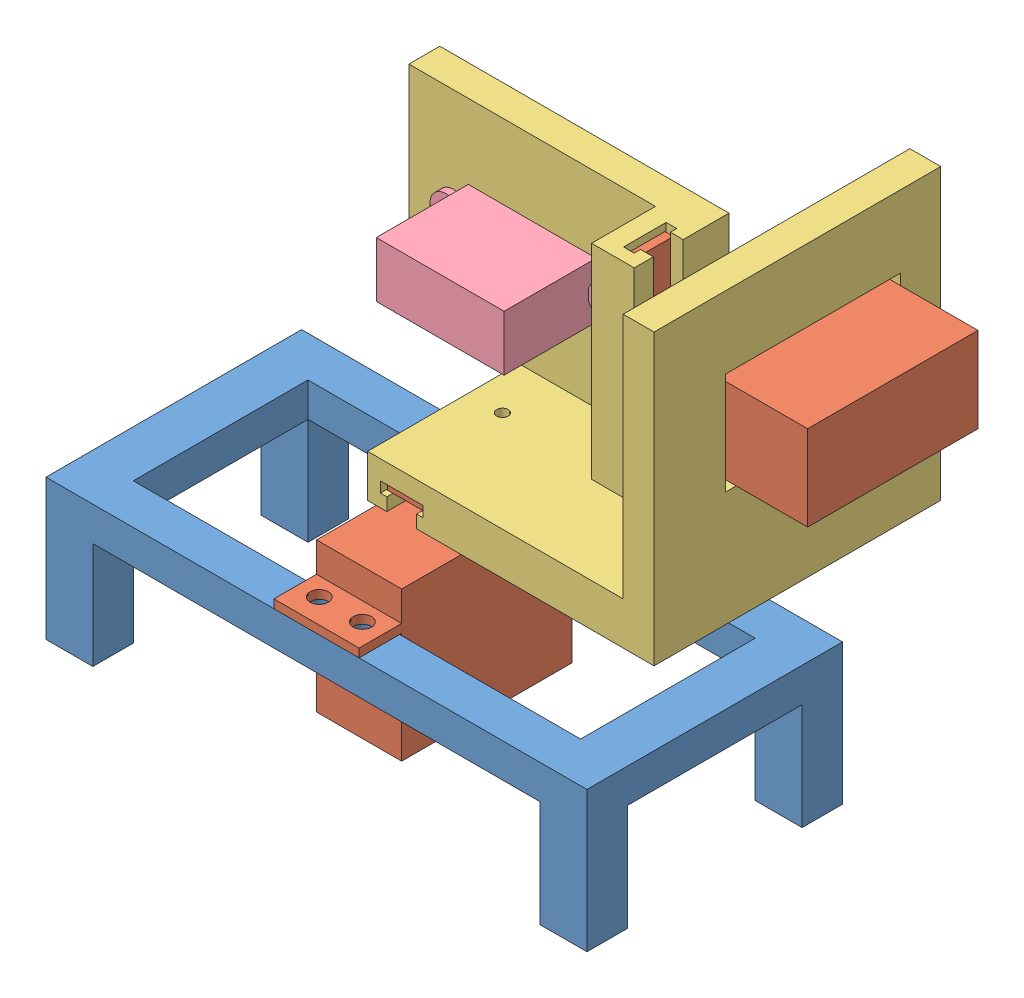
SolidWorks assembly PanTiltAssy, configuration Default. Lengths in mm.
Overall size (141.5 113.88 87.3).
6 component instances, 4 part files, 9 mates.
Components (placement in the parent):
- BaseMount-1: BaseMount [Default] at origin size (127 33 60)
- ServoBox-1: ServoBox [Default] at origin size (20 44.3 66.19)
- TiltPart-1: TiltPart [Default] at origin size (67.25 67.88 67.3)
- ServoBox-2: ServoBox [Top Version] at (52 51.94 -27.3) x (0 -1 0) z (0 0 -1) size (45.08 44.3 60)
- TiltPart-2: TiltPart [Top Part] at (51.935 65.94 -13.65) x (0 0 -1) z (0 1 0) size (22.25 67.88 48)
- DistanceSensor-1: DistanceSensor [Default] at (-0.005 51.94 -20.65) x (1 0 0) z (0 -1 0) size (44.5 21.6 13)
Mates (geometry in assembly coordinates):
- Coincident1: coincident anti-aligned: plane of TiltPart-1 through (52 23 -57.3) normal (-1 0 0); plane of ServoBox-2 through (52 51.94 -27.3) normal (1 0 0)
- Width1: width anti-aligned: plane of TiltPart-1 through (72 39.94 -47.8) normal (0 1 0); plane of ServoBox-2 through (72 63.94 -47.8) normal (0 -1 0); plane of TiltPart-1 through (43 41.94 -7.3) normal (0 -1 0); plane of ServoBox-2 through (43 61.94 -7.3) normal (0 1 0)
- Width2: width anti-aligned: plane of TiltPart-1 through (72 63.94 -6.8) normal (0 0 -1); plane of ServoBox-2 through (72 63.94 -47.8) normal (0 0 1); plane of TiltPart-1 through (50 41.94 2.7) normal (0 0 1); plane of ServoBox-2 through (50 41.94 -57.3) normal (0 0 -1)
- Width3: width anti-aligned: plane of TiltPart-2 through (33.435 27.94 -18.65) normal (0 0 1); plane of ServoBox-2 through (35.935 27.94 -8.65) normal (0 0 -1); plane of TiltPart-2 through (33.7 74.48 -18.09) normal (0 0 -1); plane of ServoBox-2 through (33.7 74.48 -9.21) normal (0 0 1)
- Width4: width aligned: plane of TiltPart-2 through (51.935 75.94 -13.65) normal (0 1 0); plane of ServoBox-2 through (51.935 27.94 -13.65) normal (0 -1 0); plane of TiltPart-2 through (33.7 74.48 -9.21) normal (0 1 0); plane of ServoBox-2 through (33.7 29.4 -9.21) normal (0 -1 0)
- Width5: width anti-aligned: plane of TiltPart-2 through (35.935 27.94 -18.65) normal (-1 0 0); plane of ServoBox-2 through (33.435 27.94 -8.65) normal (1 0 0); plane of TiltPart-2 through (35.67 51.94 -27.3) normal (1 0 0); plane of ServoBox-2 through (33.7 51.94 -27.3) normal (-1 0 0)
- Coincident3: coincident anti-aligned: plane of TiltPart-2 through (28.935 27.94 -20.65) normal (0 0 1); plane of DistanceSensor-1 through (-0.005 51.94 -20.65) normal (0 0 -1)
- Width6: width aligned: plane of TiltPart-2 through (-28.945 27.94 -20.65) normal (-1 0 0); plane of DistanceSensor-1 through (28.935 27.94 -5.65) normal (-1 0 0); plane of TiltPart-2 through (-15.005 58.44 0.95) normal (-1 0 0); plane of DistanceSensor-1 through (14.995 58.44 0.95) normal (1 0 0)
- Width7: width anti-aligned: plane of TiltPart-2 through (51.935 75.94 -13.65) normal (0 1 0); plane of DistanceSensor-1 through (51.935 27.94 -13.65) normal (0 -1 0); plane of TiltPart-2 through (-15.005 45.44 0.95) normal (0 -1 0); plane of DistanceSensor-1 through (-15.005 58.44 0.95) normal (0 1 0)
